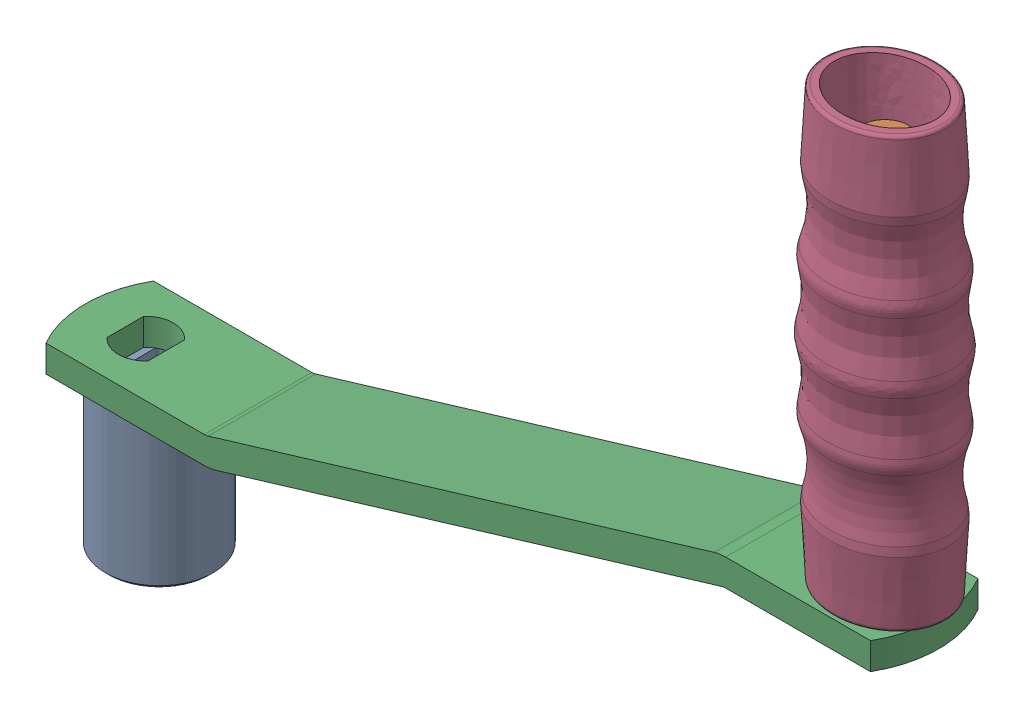
SolidWorks assembly 306132 Hex Handle, configuration Predeterminado. Lengths in mm.
Overall size (205.72 178.9 28.5).
4 component instances, 4 part files, 0 mates.
Components (placement in the parent):
- 206596 Socket-1: 206596 Socket [Predeterminado] at origin size (25.4 34.44 25.4)
- 204005 Crank Handle Pin-1: 204005 Crank Handle Pin [Predeterminado] at (171.45 67.7736 0) x (0 1 0) z (-0.529748 0 0.848155) size (101.2 19.05 19.05)
- 404234 7 Handle-1: 404234 7 Handle [Predeterminado] at (-17.4625 34.4361 0) size (201.61 42.86 25.4)
- 204004 Handle Sleeve-1: 204004 Handle Sleeve [Predeterminado] at (171.45 178.8986 0) x (0 -1 0) z (0 0 1) size (101.61 33.06 28.5)
